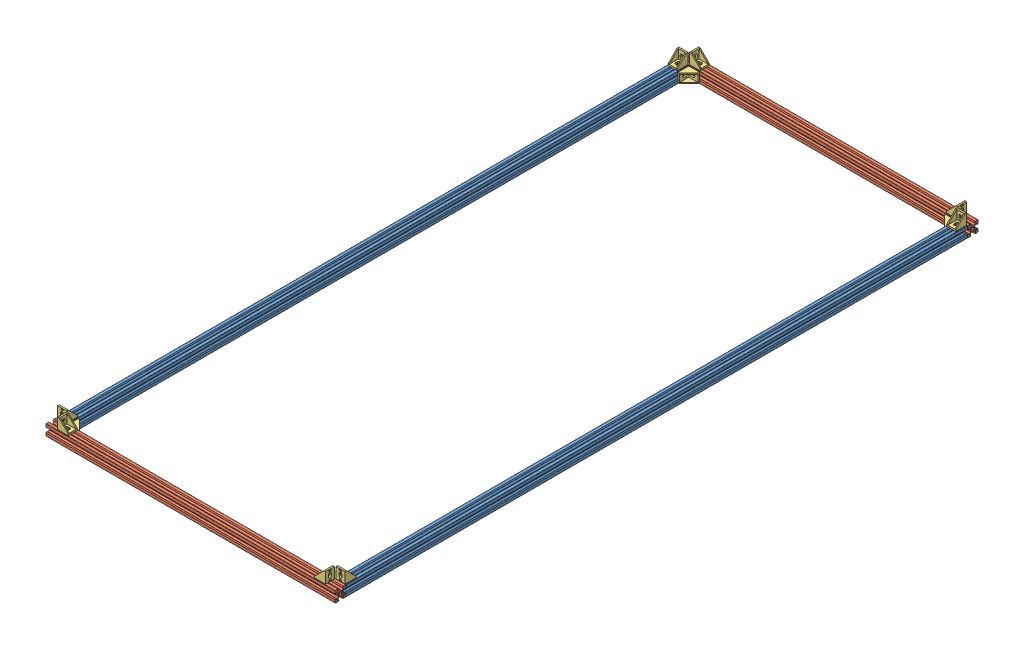
SolidWorks assembly laser base frame buttom, configuration Default. Lengths in mm.
Overall size (540 40 1200).
16 component instances, 3 part files, 74 mates.
Components (placement in the parent):
- V-Slot 20x20 X-8: V-Slot 20x20 X [Default] at (715.7702 818.7751 -1055.2654) size (20 20 1160)
- V-Slot 20x20 X-9: V-Slot 20x20 X [Default] at (1235.7702 818.7751 -1055.2654) size (20 20 1160)
- V-Slot 20x20 Y buttom-7: V-Slot 20x20 Y buttom [Default] at (705.7702 818.7751 114.7346) x (0 0 -1) z (1 0 0) size (20 20 540)
- V-Slot 20x20 Y buttom-8: V-Slot 20x20 Y buttom [Default] at (705.7702 818.7751 -1065.2654) x (0 0 -1) z (1 0 0) size (20 20 540)
- Cast Corner Bracket-1: Cast Corner Bracket [Default] at (725.7702 818.7751 104.7346) x (1 0 0) z (0 1 0) size (21 21 17)
- Cast Corner Bracket-2: Cast Corner Bracket [Default] at (715.7702 828.7751 104.7346) x (0 0 -1) z (1 0 0) size (21 21 17)
- Cast Corner Bracket-3: Cast Corner Bracket [Default] at (725.7702 828.7751 114.7346) size (21 21 17)
- Cast Corner Bracket-4: Cast Corner Bracket [Default] at (725.7702 828.7751 -1065.2654) size (21 21 17)
- Cast Corner Bracket-5: Cast Corner Bracket [Default] at (725.7702 818.7751 -1055.2654) x (1 0 0) z (0 -1 0) size (21 21 17)
- Cast Corner Bracket-6: Cast Corner Bracket [Default] at (715.7702 828.7751 -1055.2654) x (0 0 1) z (-1 0 0) size (21 21 17)
- Cast Corner Bracket-7: Cast Corner Bracket [Default] at (1225.7702 818.7751 104.7346) x (0 0 -1) z (0 1 0) size (21 21 17)
- Cast Corner Bracket-8: Cast Corner Bracket [Default] at (1225.7702 828.7751 114.7346) x (-1 0 0) z (0 0 -1) size (21 21 17)
- Cast Corner Bracket-9: Cast Corner Bracket [Default] at (1235.7702 828.7751 104.7346) x (0 0 -1) z (1 0 0) size (21 21 17)
- Cast Corner Bracket-10: Cast Corner Bracket [Default] at (1225.7702 828.7751 -1065.2654) x (-1 0 0) z (0 0 -1) size (21 21 17)
- Cast Corner Bracket-11: Cast Corner Bracket [Default] at (1225.7702 818.7751 -1055.2654) x (-1 0 0) z (0 1 0) size (21 21 17)
- Cast Corner Bracket-12: Cast Corner Bracket [Default] at (1235.7702 828.7751 -1055.2654) x (0 0 1) z (-1 0 0) size (21 21 17)
Mates (geometry in assembly coordinates):
- Coincident41: coincident aligned: plane of V-Slot 20x20 Y buttom-7 through (705.7702 818.7751 114.7346) normal (-1 0 0); plane of V-Slot 20x20 X-8 through (705.7702 818.7751 104.7346) normal (-1 0 0)
- Coincident42: coincident aligned: plane of V-Slot 20x20 Y buttom-7 through (705.7702 818.7751 114.7346) normal (-1 0 0); plane of V-Slot 20x20 X-8 through (705.7702 818.7751 104.7346) normal (-1 0 0)
- Coincident43: coincident aligned: plane of V-Slot 20x20 Y buttom-7 through (1245.7702 818.7751 114.7346) normal (1 0 0); plane of V-Slot 20x20 X-9 through (1245.7702 818.7751 104.7346) normal (1 0 0)
- Coincident44: coincident aligned: plane of V-Slot 20x20 Y buttom-7 through (1245.7702 818.7751 114.7346) normal (1 0 0); plane of V-Slot 20x20 X-9 through (1245.7702 818.7751 104.7346) normal (1 0 0)
- Coincident45: coincident aligned: plane of V-Slot 20x20 Y buttom-8 through (705.7702 818.7751 -1065.2654) normal (-1 0 0); plane of V-Slot 20x20 X-8 through (705.7702 818.7751 104.7346) normal (-1 0 0)
- Coincident46: coincident aligned: plane of V-Slot 20x20 Y buttom-8 through (705.7702 818.7751 -1065.2654) normal (-1 0 0); plane of V-Slot 20x20 X-8 through (705.7702 818.7751 104.7346) normal (-1 0 0)
- Coincident47: coincident aligned: plane of V-Slot 20x20 Y buttom-8 through (1245.7702 828.7751 -1065.2654) normal (0 1 0); plane of V-Slot 20x20 X-8 through (715.7702 828.7751 104.7346) normal (0 1 0)
- Coincident48: coincident aligned: plane of V-Slot 20x20 Y buttom-8 through (1245.7702 828.7751 -1065.2654) normal (0 1 0); plane of V-Slot 20x20 X-8 through (715.7702 828.7751 104.7346) normal (0 1 0)
- Coincident49: coincident anti-aligned: plane of V-Slot 20x20 X-8 through (715.7702 818.7751 -1055.2654) normal (0 0 -1); plane of V-Slot 20x20 Y buttom-8 through (1245.7702 818.7751 -1055.2654) normal (0 0 1)
- Coincident50: coincident anti-aligned: plane of V-Slot 20x20 X-8 through (715.7702 818.7751 -1055.2654) normal (0 0 -1); plane of V-Slot 20x20 Y buttom-8 through (1245.7702 818.7751 -1055.2654) normal (0 0 1)
- Coincident52: coincident anti-aligned: plane of V-Slot 20x20 X-9 through (1235.7702 818.7751 -1055.2654) normal (0 0 -1); plane of V-Slot 20x20 Y buttom-8 through (1245.7702 818.7751 -1055.2654) normal (0 0 1)
- Coincident53: coincident anti-aligned: plane of V-Slot 20x20 X-9 through (1235.7702 818.7751 -1055.2654) normal (0 0 -1); plane of V-Slot 20x20 Y buttom-8 through (1245.7702 818.7751 -1055.2654) normal (0 0 1)
- Coincident54: coincident aligned: plane of V-Slot 20x20 Y buttom-8 through (1245.7702 818.7751 -1065.2654) normal (1 0 0); plane of V-Slot 20x20 X-9 through (1245.7702 818.7751 104.7346) normal (1 0 0)
- Coincident55: coincident aligned: plane of V-Slot 20x20 Y buttom-8 through (1245.7702 818.7751 -1065.2654) normal (1 0 0); plane of V-Slot 20x20 X-9 through (1245.7702 818.7751 104.7346) normal (1 0 0)
- Coincident56: coincident aligned: plane of V-Slot 20x20 Y buttom-8 through (1245.7702 828.7751 -1065.2654) normal (0 1 0); plane of V-Slot 20x20 X-9 through (1235.7702 828.7751 104.7346) normal (0 1 0)
- Coincident57: coincident aligned: plane of V-Slot 20x20 Y buttom-8 through (1245.7702 828.7751 -1065.2654) normal (0 1 0); plane of V-Slot 20x20 X-9 through (1235.7702 828.7751 104.7346) normal (0 1 0)
- Coincident58: coincident aligned: plane of V-Slot 20x20 Y buttom-7 through (1245.7702 828.7751 114.7346) normal (0 1 0); plane of V-Slot 20x20 X-9 through (1235.7702 828.7751 104.7346) normal (0 1 0)
- Coincident59: coincident aligned: plane of V-Slot 20x20 Y buttom-7 through (1245.7702 828.7751 114.7346) normal (0 1 0); plane of V-Slot 20x20 X-9 through (1235.7702 828.7751 104.7346) normal (0 1 0)
- Coincident60: coincident aligned: plane of V-Slot 20x20 Y buttom-7 through (1245.7702 828.7751 114.7346) normal (0 1 0); plane of V-Slot 20x20 X-8 through (715.7702 828.7751 104.7346) normal (0 1 0)
- Coincident61: coincident aligned: plane of V-Slot 20x20 Y buttom-7 through (1245.7702 828.7751 114.7346) normal (0 1 0); plane of V-Slot 20x20 X-8 through (715.7702 828.7751 104.7346) normal (0 1 0)
- Width1: width: plane of V-Slot 20x20 X-8 through (718.8952 818.7751 104.7346) normal (-1 0 0); plane of V-Slot 20x20 X-8 through (712.6452 818.7751 104.7346) normal (1 0 0); plane of Cast Corner Bracket-2 through (717.7702 828.7751 94.5995) normal (1 0 0); plane of Cast Corner Bracket-2 through (713.7702 828.7751 94.5995) normal (-1 0 0)
- Width2: width anti-aligned: plane of V-Slot 20x20 Y buttom-7 through (1245.7702 821.9001 114.7346) normal (0 -1 0); plane of V-Slot 20x20 Y buttom-7 through (1245.7702 815.6501 114.7346) normal (0 1 0); plane of Cast Corner Bracket-1 through (725.7702 820.7751 104.7346) normal (0 1 0); plane of Cast Corner Bracket-1 through (725.7702 816.7751 104.7346) normal (0 -1 0)
- Coincident62: coincident: plane of Cast Corner Bracket-2 through (724.2702 828.7751 94.5995) normal (0 -1 0); plane of V-Slot 20x20 X-8 through (715.7702 828.7751 104.7346) normal (0 1 0)
- Coincident63: coincident: plane of Cast Corner Bracket-2 through (724.2702 828.7751 94.5995) normal (0 -1 0); plane of V-Slot 20x20 X-8 through (715.7702 828.7751 104.7346) normal (0 1 0)
- Coincident64: coincident anti-aligned: plane of Cast Corner Bracket-1 through (725.7702 827.2751 104.7346) normal (0 0 1); plane of V-Slot 20x20 Y buttom-7 through (1245.7702 818.7751 104.7346) normal (0 0 -1)
- Coincident65: coincident anti-aligned: plane of Cast Corner Bracket-1 through (725.7702 827.2751 104.7346) normal (0 0 1); plane of V-Slot 20x20 Y buttom-7 through (1245.7702 818.7751 104.7346) normal (0 0 -1)
- Width3: width: plane of V-Slot 20x20 Y buttom-7 through (1245.7702 818.7751 111.6096) normal (0 0 1); plane of V-Slot 20x20 Y buttom-7 through (1245.7702 818.7751 117.8596) normal (0 0 -1); plane of Cast Corner Bracket-3 through (752.1617 828.7751 112.7346) normal (0 0 -1); plane of Cast Corner Bracket-3 through (752.1617 828.7751 116.7346) normal (0 0 1)
- Coincident66: coincident: plane of Cast Corner Bracket-3 through (752.1617 828.7751 123.2346) normal (0 -1 0); plane of V-Slot 20x20 Y buttom-7 through (1245.7702 828.7751 114.7346) normal (0 1 0)
- Coincident67: coincident: plane of Cast Corner Bracket-3 through (752.1617 828.7751 123.2346) normal (0 -1 0); plane of V-Slot 20x20 Y buttom-7 through (1245.7702 828.7751 114.7346) normal (0 1 0)
- Coincident68: coincident anti-aligned: plane of V-Slot 20x20 X-8 through (715.7702 818.7751 104.7346) normal (0 0 1); plane of V-Slot 20x20 Y buttom-7 through (1245.7702 818.7751 104.7346) normal (0 0 -1)
- Coincident69: coincident anti-aligned: plane of V-Slot 20x20 X-8 through (715.7702 818.7751 104.7346) normal (0 0 1); plane of V-Slot 20x20 Y buttom-7 through (1245.7702 818.7751 104.7346) normal (0 0 -1)
- Width4: width anti-aligned: plane of V-Slot 20x20 X-9 through (1235.7702 821.9001 104.7346) normal (0 -1 0); plane of V-Slot 20x20 X-9 through (1235.7702 815.6501 104.7346) normal (0 1 0); plane of Cast Corner Bracket-11 through (1225.7702 820.7751 -1055.2654) normal (0 1 0); plane of Cast Corner Bracket-11 through (1225.7702 816.7751 -1055.2654) normal (0 -1 0)
- Width5: width: plane of V-Slot 20x20 Y buttom-8 through (1245.7702 818.7751 -1068.3904) normal (0 0 1); plane of V-Slot 20x20 Y buttom-8 through (1245.7702 818.7751 -1062.1404) normal (0 0 -1); plane of Cast Corner Bracket-10 through (1194.0317 828.7751 -1067.2654) normal (0 0 -1); plane of Cast Corner Bracket-10 through (1194.0317 828.7751 -1063.2654) normal (0 0 1)
- Width6: width: plane of V-Slot 20x20 X-9 through (1232.6452 818.7751 104.7346) normal (1 0 0); plane of V-Slot 20x20 X-9 through (1238.8952 818.7751 104.7346) normal (-1 0 0); plane of Cast Corner Bracket-12 through (1237.7702 828.7751 -992.4235) normal (1 0 0); plane of Cast Corner Bracket-12 through (1233.7702 828.7751 -992.4235) normal (-1 0 0)
- Coincident70: coincident: plane of Cast Corner Bracket-12 through (1227.2702 828.7751 -992.4235) normal (0 -1 0); plane of V-Slot 20x20 X-9 through (1235.7702 828.7751 104.7346) normal (0 1 0)
- Coincident71: coincident: plane of Cast Corner Bracket-12 through (1227.2702 828.7751 -992.4235) normal (0 -1 0); plane of V-Slot 20x20 X-9 through (1235.7702 828.7751 104.7346) normal (0 1 0)
- Coincident72: coincident anti-aligned: plane of Cast Corner Bracket-11 through (1225.7702 827.2751 -1035.2654) normal (1 0 0); plane of V-Slot 20x20 X-9 through (1225.7702 818.7751 104.7346) normal (-1 0 0)
- Coincident73: coincident anti-aligned: plane of Cast Corner Bracket-11 through (1225.7702 827.2751 -1035.2654) normal (1 0 0); plane of V-Slot 20x20 X-9 through (1225.7702 818.7751 104.7346) normal (-1 0 0)
- Coincident74: coincident anti-aligned: plane of Cast Corner Bracket-11 through (1225.7702 827.2751 -1055.2654) normal (0 0 -1); plane of V-Slot 20x20 Y buttom-8 through (1245.7702 818.7751 -1055.2654) normal (0 0 1)
- Coincident75: coincident anti-aligned: plane of Cast Corner Bracket-11 through (1225.7702 827.2751 -1055.2654) normal (0 0 -1); plane of V-Slot 20x20 Y buttom-8 through (1245.7702 818.7751 -1055.2654) normal (0 0 1)
- Coincident76: coincident: plane of Cast Corner Bracket-10 through (1194.0317 828.7751 -1073.7654) normal (0 -1 0); plane of V-Slot 20x20 Y buttom-8 through (1245.7702 828.7751 -1065.2654) normal (0 1 0)
- Coincident77: coincident: plane of Cast Corner Bracket-10 through (1194.0317 828.7751 -1073.7654) normal (0 -1 0); plane of V-Slot 20x20 Y buttom-8 through (1245.7702 828.7751 -1065.2654) normal (0 1 0)
- Coincident78: coincident anti-aligned: plane of Cast Corner Bracket-1 through (725.7702 827.2751 84.7346) normal (-1 0 0); plane of V-Slot 20x20 X-8 through (725.7702 818.7751 104.7346) normal (1 0 0)
- Coincident79: coincident anti-aligned: plane of Cast Corner Bracket-1 through (725.7702 827.2751 84.7346) normal (-1 0 0); plane of V-Slot 20x20 X-8 through (725.7702 818.7751 104.7346) normal (1 0 0)
- Width7: width anti-aligned: plane of V-Slot 20x20 X-8 through (715.7702 815.6501 104.7346) normal (0 1 0); plane of V-Slot 20x20 X-8 through (715.7702 821.9001 104.7346) normal (0 -1 0); plane of Cast Corner Bracket-5 through (725.7702 816.7751 -1055.2654) normal (0 -1 0); plane of Cast Corner Bracket-5 through (725.7702 820.7751 -1055.2654) normal (0 1 0)
- Width8: width: plane of V-Slot 20x20 Y buttom-8 through (1245.7702 818.7751 -1068.3904) normal (0 0 1); plane of V-Slot 20x20 Y buttom-8 through (1245.7702 818.7751 -1062.1404) normal (0 0 -1); plane of Cast Corner Bracket-4 through (758.2714 828.7751 -1067.2654) normal (0 0 -1); plane of Cast Corner Bracket-4 through (758.2714 828.7751 -1063.2654) normal (0 0 1)
- Width9: width: plane of V-Slot 20x20 X-8 through (712.6452 818.7751 104.7346) normal (1 0 0); plane of V-Slot 20x20 X-8 through (718.8952 818.7751 104.7346) normal (-1 0 0); plane of Cast Corner Bracket-6 through (713.7702 828.7751 -1055.0953) normal (-1 0 0); plane of Cast Corner Bracket-6 through (717.7702 828.7751 -1055.0953) normal (1 0 0)
- Coincident80: coincident: plane of Cast Corner Bracket-6 through (707.2702 828.7751 -1055.0953) normal (0 -1 0); plane of V-Slot 20x20 X-8 through (715.7702 828.7751 104.7346) normal (0 1 0)
- Coincident81: coincident: plane of Cast Corner Bracket-6 through (707.2702 828.7751 -1055.0953) normal (0 -1 0); plane of V-Slot 20x20 X-8 through (715.7702 828.7751 104.7346) normal (0 1 0)
- Coincident82: coincident anti-aligned: plane of Cast Corner Bracket-5 through (725.7702 810.2751 -1055.2654) normal (0 0 -1); plane of V-Slot 20x20 Y buttom-8 through (1245.7702 818.7751 -1055.2654) normal (0 0 1)
- Coincident83: coincident anti-aligned: plane of Cast Corner Bracket-5 through (725.7702 810.2751 -1055.2654) normal (0 0 -1); plane of V-Slot 20x20 Y buttom-8 through (1245.7702 818.7751 -1055.2654) normal (0 0 1)
- Coincident84: coincident anti-aligned: plane of Cast Corner Bracket-5 through (725.7702 810.2751 -1035.2654) normal (-1 0 0); plane of V-Slot 20x20 X-8 through (725.7702 818.7751 104.7346) normal (1 0 0)
- Coincident85: coincident anti-aligned: plane of Cast Corner Bracket-5 through (725.7702 810.2751 -1035.2654) normal (-1 0 0); plane of V-Slot 20x20 X-8 through (725.7702 818.7751 104.7346) normal (1 0 0)
- Coincident86: coincident: plane of Cast Corner Bracket-4 through (758.2714 828.7751 -1056.7654) normal (0 -1 0); plane of V-Slot 20x20 Y buttom-8 through (1245.7702 828.7751 -1065.2654) normal (0 1 0)
- Coincident87: coincident: plane of Cast Corner Bracket-4 through (758.2714 828.7751 -1056.7654) normal (0 -1 0); plane of V-Slot 20x20 Y buttom-8 through (1245.7702 828.7751 -1065.2654) normal (0 1 0)
- Width10: width: plane of V-Slot 20x20 X-9 through (1232.6452 818.7751 104.7346) normal (1 0 0); plane of V-Slot 20x20 X-9 through (1238.8952 818.7751 104.7346) normal (-1 0 0); plane of Cast Corner Bracket-9 through (1237.7702 828.7751 69.2908) normal (1 0 0); plane of Cast Corner Bracket-9 through (1233.7702 828.7751 69.2908) normal (-1 0 0)
- Width11: width aligned: plane of V-Slot 20x20 X-9 through (1235.7702 815.6501 104.7346) normal (0 1 0); plane of V-Slot 20x20 X-9 through (1235.7702 821.9001 104.7346) normal (0 -1 0); plane of Cast Corner Bracket-7 through (1225.7702 820.7751 104.7346) normal (0 1 0); plane of Cast Corner Bracket-7 through (1225.7702 816.7751 104.7346) normal (0 -1 0)
- Width12: width: plane of V-Slot 20x20 Y buttom-7 through (1245.7702 818.7751 117.8596) normal (0 0 -1); plane of V-Slot 20x20 Y buttom-7 through (1245.7702 818.7751 111.6096) normal (0 0 1); plane of Cast Corner Bracket-8 through (1212.9698 828.7751 112.7346) normal (0 0 -1); plane of Cast Corner Bracket-8 through (1212.9698 828.7751 116.7346) normal (0 0 1)
- Coincident88: coincident: plane of Cast Corner Bracket-8 through (1212.9698 828.7751 106.2346) normal (0 -1 0); plane of V-Slot 20x20 Y buttom-7 through (1245.7702 828.7751 114.7346) normal (0 1 0)
- Coincident89: coincident: plane of Cast Corner Bracket-8 through (1212.9698 828.7751 106.2346) normal (0 -1 0); plane of V-Slot 20x20 Y buttom-7 through (1245.7702 828.7751 114.7346) normal (0 1 0)
- Coincident90: coincident anti-aligned: plane of Cast Corner Bracket-7 through (1205.7702 827.2751 104.7346) normal (0 0 1); plane of V-Slot 20x20 Y buttom-7 through (1245.7702 818.7751 104.7346) normal (0 0 -1)
- Coincident91: coincident anti-aligned: plane of Cast Corner Bracket-7 through (1205.7702 827.2751 104.7346) normal (0 0 1); plane of V-Slot 20x20 Y buttom-7 through (1245.7702 818.7751 104.7346) normal (0 0 -1)
- Coincident92: coincident: plane of Cast Corner Bracket-9 through (1244.2702 828.7751 69.2908) normal (0 -1 0); plane of V-Slot 20x20 X-9 through (1235.7702 828.7751 104.7346) normal (0 1 0)
- Coincident93: coincident: plane of Cast Corner Bracket-9 through (1244.2702 828.7751 69.2908) normal (0 -1 0); plane of V-Slot 20x20 X-9 through (1235.7702 828.7751 104.7346) normal (0 1 0)
- Coincident94: coincident anti-aligned: plane of Cast Corner Bracket-7 through (1225.7702 827.2751 104.7346) normal (1 0 0); plane of V-Slot 20x20 X-9 through (1225.7702 818.7751 104.7346) normal (-1 0 0)
- Coincident95: coincident anti-aligned: plane of Cast Corner Bracket-7 through (1225.7702 827.2751 104.7346) normal (1 0 0); plane of V-Slot 20x20 X-9 through (1225.7702 818.7751 104.7346) normal (-1 0 0)
- Coincident96: coincident aligned: plane of V-Slot 20x20 X-9 through (1235.7702 818.7751 104.7346) normal (0 0 1); plane of Cast Corner Bracket-9 through (1244.2702 848.7751 104.7346) normal (0 0 1)
- Distance1: distance = 20 mm aligned: plane of Cast Corner Bracket-8 through (1225.7702 848.7751 106.2346) normal (1 0 0); plane of V-Slot 20x20 Y buttom-7 through (1245.7702 818.7751 114.7346) normal (1 0 0)
- Coincident98: coincident aligned: plane of V-Slot 20x20 X-8 through (715.7702 818.7751 104.7346) normal (0 0 1); plane of Cast Corner Bracket-2 through (724.2702 848.7751 104.7346) normal (0 0 1)
- Distance2: distance = 20 mm aligned: plane of Cast Corner Bracket-3 through (725.7702 848.7751 123.2346) normal (-1 0 0); plane of V-Slot 20x20 Y buttom-7 through (705.7702 818.7751 114.7346) normal (-1 0 0)
- Coincident99: coincident aligned: plane of V-Slot 20x20 X-8 through (715.7702 818.7751 -1055.2654) normal (0 0 -1); plane of Cast Corner Bracket-6 through (707.2702 848.7751 -1055.2654) normal (0 0 -1)
- Distance3: distance = 20 mm aligned: plane of Cast Corner Bracket-4 through (725.7702 848.7751 -1056.7654) normal (-1 0 0); plane of V-Slot 20x20 Y buttom-8 through (705.7702 818.7751 -1065.2654) normal (-1 0 0)
- Distance4: distance = 20 mm aligned: plane of Cast Corner Bracket-10 through (1225.7702 848.7751 -1073.7654) normal (1 0 0); plane of V-Slot 20x20 Y buttom-8 through (1245.7702 818.7751 -1065.2654) normal (1 0 0)
- Coincident100: coincident aligned: plane of V-Slot 20x20 X-9 through (1235.7702 818.7751 -1055.2654) normal (0 0 -1); plane of Cast Corner Bracket-12 through (1227.2702 848.7751 -1055.2654) normal (0 0 -1)
